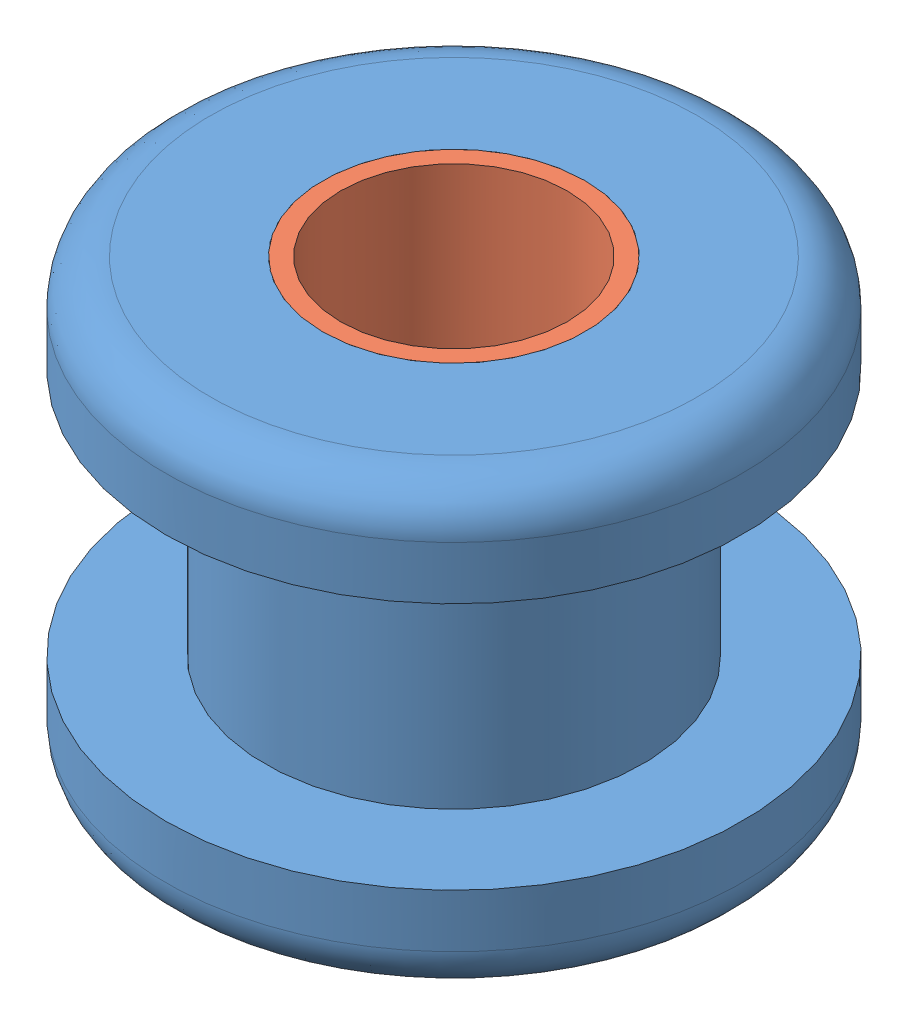
SolidWorks assembly FS5109M_Ensemble silent-bloc, configuration Défaut. Lengths in mm.
Overall size (6.5 5.2 6.5).
2 component instances, 2 part files, 4 mates.
Components (placement in the parent):
- FS5109M_silent-bloc-1: FS5109M_silent-bloc [Défaut] at origin size (6.5 5 6.5)
- FS5109M_silent-bloc_douille-1: FS5109M_silent-bloc_douille [Défaut] at (0 -2.7 0) x (-1 0 0) z (0 0 1) size (4.5 5.2 4.5)
Mates (geometry in assembly coordinates):
- Coïncidente1: coordinate: point of FS5109M_silent-bloc-1
- Coïncidente2: coincident aligned: plane of FS5109M_silent-bloc-1 through (0 0 0) normal (0 0 1); plane of FS5109M_silent-bloc_douille-1 through (0 -2.7 0) normal (0 0 1)
- Coïncidente3: coincident anti-aligned: plane of FS5109M_silent-bloc-1 through (0 0 0) normal (1 0 0); plane of FS5109M_silent-bloc_douille-1 through (0 -2.7 0) normal (-1 0 0)
- Coïncidente4: coincident aligned: plane of FS5109M_silent-bloc-1 through (-2.75 2.5 0) normal (0 1 0); plane of FS5109M_silent-bloc_douille-1 through (1.28 2.5 0) normal (0 1 0)
